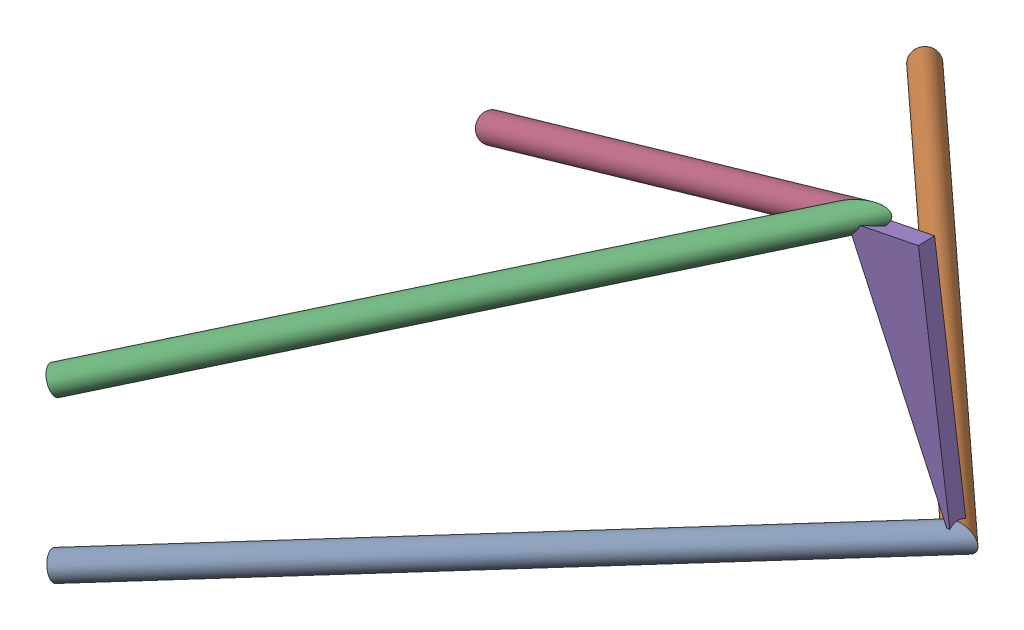
SolidWorks assembly 240008, configuration Default. Lengths in mm.
Overall size (519.27 346.1 663.6).
3 component instances, 3 part files, 6 mates.
Components (placement in the parent):
- 240015-1: 240015 [Default<As Machined>] at (16.2337 -158.3384 0) x (-0.979196 -0.202918 0) z (0 0 1) size (510.86 69.94 663.6)
- 240014-1: 240014 [Default<As Machined>] at (-45.9439 195.3868 0) x (-0.933785 -0.357833 0) z (0 0 1) size (465.32 63.98 343.2)
- 240013-1: 240013 [Default] at (17.9518 111.8045 -1.4531) x (-0.054042 -0.024885 -0.998229) z (0.986736 0.15192 -0.057207) size (12.7 177.8 50.8)
Mates (geometry in assembly coordinates):
- Coincident1: coincident aligned: line of 240015-1 through (-435 -124.6 206.8) axis (0 0 -1)
- Coincident3: coincident aligned: line of 240014-1 through (-435 -5 206.8) axis (0 0 -1)
- Coincident4: coincident: point of 240014-1; point of assembly
- Coincident5: coincident: point of assembly; point of 240014-1; point of 240013-1
- Coincident6: coincident: point of assembly; point of 240015-1; point of 240013-1
- Coincident7: coincident: point of 240015-1; point of assembly
